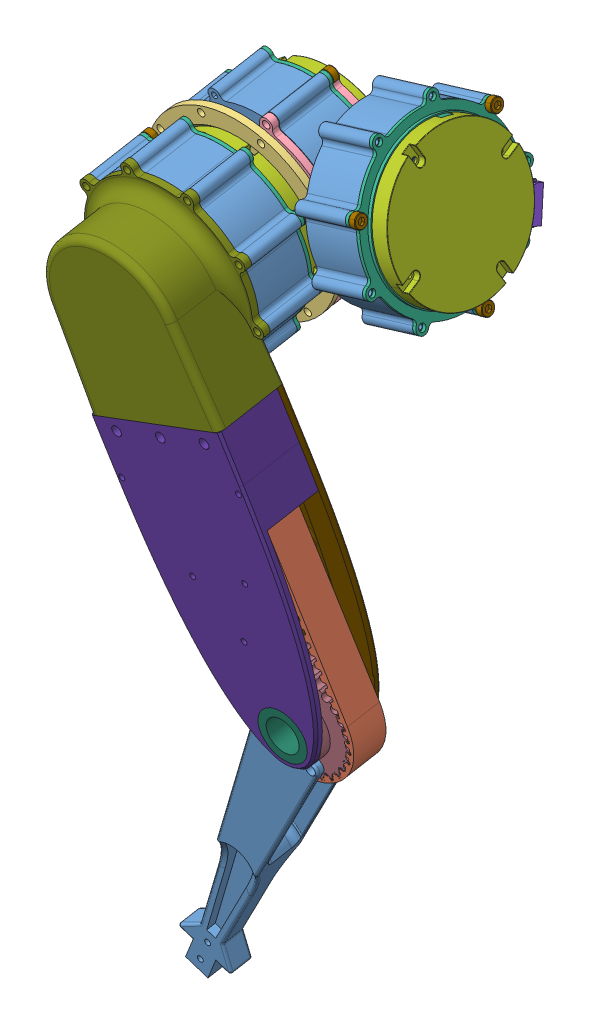
SolidWorks assembly 左机械腿装配体, configuration 默认. Lengths in mm.
Overall size (149.76 378.63 154.43).
74 component instances, 22 part files, 39 mates.
Components (placement in the parent):
- CyberGearmotor.stp-1: CyberGearmotor.stp [默认] at (88.0352 214.6966 202.2626) x (-0.711569 -0.699745 -0.063453) z (-0.039645 0.130153 -0.990701) size (96.28 96.17 36.5)
  - ASM0002_ASM_1_ASM.stp-1: ASM0002_ASM_1_ASM.stp [默认] at origin size (96.28 96.17 36.5)
    - ASM0002_ASM_1_ASM_1_ASM.stp-1: ASM0002_ASM_1_ASM_1_ASM.stp [默认] at origin size (96.28 96.17 36.5)
      - 0714_ASM_1_ASM_1_ASM_1_ASM.stp-1: 0714_ASM_1_ASM_1_ASM_1_ASM.stp [默认] at origin size (96.28 96.17 36.5)
        - 3_1_02_067_0003_ASM_ASM_1_ASM_1_ASM.stp-1: 3_1_02_067_0003_ASM_ASM_1_ASM_1_ASM.stp [默认] at origin size (96.28 96.17 36.5)
          - 3_1_02_067_0003_ASM_1_ASM_1_ASM_ASM.stp-1: 3_1_02_067_0003_ASM_1_ASM_1_ASM_ASM.stp [默认] at origin size (96.28 96.17 36.5)
            - 1_1_06_EB673-504_1_1_1_1_1.stp-1: 1_1_06_EB673-504_1_1_1_1_1.stp [默认] at (39.8324 39.833 -22) size (79.19 78.95 25.5)
            - 1_2_04_670601_1_1_1_1_1.stp-1: 1_2_04_670601_1_1_1_1_1.stp [默认] at (93.9161 79.9966 -44) size (37 37 4)
            - 1_1_02_EB671-500_1_1_1_1_1.stp-1: 1_1_02_EB671-500_1_1_1_1_1.stp [默认] at (93.9161 79.9966 -44.4) x (-0.960973 0.276644 0) z (0 0 1) size (33 33 8.5)
            - 1_2_04_694000_1_1_1_1_1.stp-1: 1_2_04_694000_1_1_1_1_1.stp [默认] at (93.9161 79.9966 -44.5) size (11 11 4)
            - 1_2_06_000213_1_1_1_1_1.stp-1: 1_2_06_000213_1_1_1_1_1.stp [默认] at (93.9161 79.9966 -45.5) size (38.8 36.2 1.5)
            - 1_1_31_QT-642_1_1_1_1_1.stp-1: 1_1_31_QT-642_1_1_1_1_1.stp [默认] at (93.9161 79.9966 -22) x (-0.970555 -0.24088 0) z (0 0 -1) size (79.5 79.36 6)
            - 1_1_06_EB673-502_1_1_1_1_1.stp-1: 1_1_06_EB673-502_1_1_1_1_1.stp [默认] at (93.9161 79.9966 -13) x (-0.515958 -0.856614 0) z (0 0 -1) size (63 63 8)
          - 0518_ASM_2_ASM_1_ASM_1_ASM_1_AS_ASM.stp-1: 0518_ASM_2_ASM_1_ASM_1_ASM_1_AS_ASM.stp [默认] at (93.9161 79.9966 -17.235) x (0.235897 -0.971778 0) z (0 0 1) size (15.5 11.3 5.2)
            - 12345_ASM_1_ASM_2_ASM_1_ASM_1_A_ASM.stp-1: 12345_ASM_1_ASM_2_ASM_1_ASM_1_A_ASM.stp [默认] at origin size (15.5 11.3 5.2)
              - DUANZI_1_3_1_1_1_1_1_1.stp-1: DUANZI_1_3_1_1_1_1_1_1.stp [默认] at (-0.1798 16.5474 0.4329) x (0 0 -1) z (0 1 0) size (5.2 15.5 11.3)
      - LUODING_1_1.stp-1: LUODING_1_1.stp [默认] at (119.9375 52.9941 -20.5) x (-1 0 0) z (0 1 0) size (5.68 3 5.68)
      - LUODING_1_1.stp-2: LUODING_1_1.stp [默认] at (104.2902 116.0331 -20.5) x (-1 0 0) z (0 1 0) size (5.68 3 5.68)
      - LUODING_1_1.stp-3: LUODING_1_1.stp [默认] at (57.5205 70.9626 -20.5) x (-1 0 0) z (0 1 0) size (5.68 3 5.68)
  - 0411-2_4_1_3_1.stp-1: 0411-2_4_1_3_1.stp [默认] at (93.9161 79.9964 -17.5) x (0.235904 -0.971776 0) z (0 0 1) size (58 56.68 1.62)
- 带轮-1: 带轮 [默认] at (-32.2576 196.3768 272.8032) x (-0.787561 0.606131 0.111146) z (-0.039645 0.130153 -0.990701) size (43.22 43.22 15)
- 带轮挡边-1: 带轮挡边 [默认] at (-32.8286 198.3388 257.943) x (-0.787561 0.606131 0.111146) z (-0.039645 0.130153 -0.990701) size (50 50 4)
- 带轮挡边-2: 带轮挡边 [默认] at (-32.0753 195.8659 276.7664) x (-0.136683 -0.982867 -0.123654) z (-0.039645 0.130153 -0.990701) size (50 50 4)
- 膝关节带轮-1: 膝关节带轮 [默认] at (42.7569 42.5696 249.5951) x (0.905586 -0.414358 -0.090675) z (-0.039645 0.130153 -0.990701) size (43.22 43.22 23)
- 轴承-1: 轴承 [默认] at (22.237 54.4332 233.3012) x (-0.618855 -0.781631 -0.077921) z (0.039645 -0.130153 0.990701) size (23 23 4)
- 轴承-2: 轴承 [默认] at (22.9704 52.0254 251.6291) x (0.937799 -0.337392 -0.081853) z (0.039645 -0.130153 0.990701) size (23 23 4)
- 膝关节转轴-1: 膝关节转轴 [默认] at (22.1378 54.7586 230.8244) x (-0.610217 -0.788272 -0.079139) z (0.039645 -0.130153 0.990701) size (21 21 29)
- 大腿根部SLDPRT-3: 大腿根部SLDPRT [默认] at (-27.5965 273.8808 260.5922) x (-0.568547 0.812397 0.12948) z (0.039645 -0.130153 0.990701) size (94.61 80.08 30.19)
- 大腿前部-1: 大腿前部 [默认] at (-12.0598 121.0935 270.1798) x (-0.934453 -0.355964 -0.00937) z (0.353874 -0.925392 -0.135734) size (62 27.01 128.98)
- 大腿前部盖子-1: 大腿前部盖子 [默认] at (1.6543 130.6753 240.6082) x (0.934453 0.355964 0.00937) z (0.353874 -0.925392 -0.135734) size (62 3.5 129)
- 小腿2-1: 小腿2 [默认] at (-5.1862 -5.3475 232.6012) x (-0.422306 -0.90076 -0.101437) z (-0.905586 0.414358 0.090675) size (141.69 21.45 28.63)
- 5m同步带1-1: 5m同步带1 [默认] at (22.3227 53.9177 244.3332) x (0.039645 -0.130153 0.990701) z (0.353874 -0.925392 -0.135734) size (15 46.9 201.91)
- 连接盘-1: 连接盘 [默认] at (-34.2196 204.9655 212.9422) x (-0.449194 0.883325 0.134022) z (0.892554 0.45033 0.023444) size (80.5 13.5 80.5)
- CyberGearmotor.stp-2: CyberGearmotor.stp [默认] at (42.1725 305.1021 174.0853) x (0.012772 -0.991334 -0.130747) z (-0.039645 0.130153 -0.990701) size (96.28 96.17 36.5)
  - ASM0002_ASM_1_ASM.stp-1: ASM0002_ASM_1_ASM.stp [默认] at origin size (96.28 96.17 36.5)
    - ASM0002_ASM_1_ASM_1_ASM.stp-1: ASM0002_ASM_1_ASM_1_ASM.stp [默认] at origin size (96.28 96.17 36.5)
      - 0714_ASM_1_ASM_1_ASM_1_ASM.stp-1: 0714_ASM_1_ASM_1_ASM_1_ASM.stp [默认] at origin size (96.28 96.17 36.5)
        - 3_1_02_067_0003_ASM_ASM_1_ASM_1_ASM.stp-1: 3_1_02_067_0003_ASM_ASM_1_ASM_1_ASM.stp [默认] at origin size (96.28 96.17 36.5)
          - 3_1_02_067_0003_ASM_1_ASM_1_ASM_ASM.stp-1: 3_1_02_067_0003_ASM_1_ASM_1_ASM_ASM.stp [默认] at origin size (96.28 96.17 36.5)
            - 1_1_06_EB673-504_1_1_1_1_1.stp-1: 1_1_06_EB673-504_1_1_1_1_1.stp [默认] at (39.8324 39.833 -22) size (79.19 78.95 25.5)
            - 1_2_04_670601_1_1_1_1_1.stp-1: 1_2_04_670601_1_1_1_1_1.stp [默认] at (93.9161 79.9966 -44) size (37 37 4)
            - 1_1_02_EB671-500_1_1_1_1_1.stp-1: 1_1_02_EB671-500_1_1_1_1_1.stp [默认] at (93.9161 79.9966 -44.4) x (-0.960973 0.276644 0) z (0 0 1) size (33 33 8.5)
            - 1_2_04_694000_1_1_1_1_1.stp-1: 1_2_04_694000_1_1_1_1_1.stp [默认] at (93.9161 79.9966 -44.5) size (11 11 4)
            - 1_2_06_000213_1_1_1_1_1.stp-1: 1_2_06_000213_1_1_1_1_1.stp [默认] at (93.9161 79.9966 -45.5) size (38.8 36.2 1.5)
            - 1_1_31_QT-642_1_1_1_1_1.stp-1: 1_1_31_QT-642_1_1_1_1_1.stp [默认] at (93.9161 79.9966 -22) x (-0.970555 -0.24088 0) z (0 0 -1) size (79.5 79.36 6)
            - 1_1_06_EB673-502_1_1_1_1_1.stp-1: 1_1_06_EB673-502_1_1_1_1_1.stp [默认] at (93.9161 79.9966 -13) x (-0.515958 -0.856614 0) z (0 0 -1) size (63 63 8)
          - 0518_ASM_2_ASM_1_ASM_1_ASM_1_AS_ASM.stp-1: 0518_ASM_2_ASM_1_ASM_1_ASM_1_AS_ASM.stp [默认] at (93.9161 79.9966 -17.235) x (0.235897 -0.971778 0) z (0 0 1) size (15.5 11.3 5.2)
            - 12345_ASM_1_ASM_2_ASM_1_ASM_1_A_ASM.stp-1: 12345_ASM_1_ASM_2_ASM_1_ASM_1_A_ASM.stp [默认] at origin size (15.5 11.3 5.2)
              - DUANZI_1_3_1_1_1_1_1_1.stp-1: DUANZI_1_3_1_1_1_1_1_1.stp [默认] at (-0.1798 16.5474 0.4329) x (0 0 -1) z (0 1 0) size (5.2 15.5 11.3)
      - LUODING_1_1.stp-1: LUODING_1_1.stp [默认] at (119.9375 52.9941 -20.5) x (-1 0 0) z (0 1 0) size (5.68 3 5.68)
      - LUODING_1_1.stp-2: LUODING_1_1.stp [默认] at (104.2902 116.0331 -20.5) x (-1 0 0) z (0 1 0) size (5.68 3 5.68)
      - LUODING_1_1.stp-3: LUODING_1_1.stp [默认] at (57.5205 70.9626 -20.5) x (-1 0 0) z (0 1 0) size (5.68 3 5.68)
  - 0411-2_4_1_3_1.stp-1: 0411-2_4_1_3_1.stp [默认] at (93.9161 79.9964 -17.5) x (0.235904 -0.971776 0) z (0 0 1) size (58 56.68 1.62)
- 肩关节连接器-1: 肩关节连接器 [默认] at (-0.5795 143.262 203.6917) x (0.012746 -0.991334 -0.130746) z (0.999133 0.017811 -0.037643) size (67.92 36.71 40.7)
- CyberGearmotor.stp-3: CyberGearmotor.stp [默认] at (56.3683 218.9179 320.1116) x (0.161386 -0.529819 -0.832614) z (0.956605 0.291387 0) size (96.28 96.17 36.5)
  - ASM0002_ASM_1_ASM.stp-1: ASM0002_ASM_1_ASM.stp [默认] at origin size (96.28 96.17 36.5)
    - ASM0002_ASM_1_ASM_1_ASM.stp-1: ASM0002_ASM_1_ASM_1_ASM.stp [默认] at origin size (96.28 96.17 36.5)
      - 0714_ASM_1_ASM_1_ASM_1_ASM.stp-1: 0714_ASM_1_ASM_1_ASM_1_ASM.stp [默认] at origin size (96.28 96.17 36.5)
        - 3_1_02_067_0003_ASM_ASM_1_ASM_1_ASM.stp-1: 3_1_02_067_0003_ASM_ASM_1_ASM_1_ASM.stp [默认] at origin size (96.28 96.17 36.5)
          - 3_1_02_067_0003_ASM_1_ASM_1_ASM_ASM.stp-1: 3_1_02_067_0003_ASM_1_ASM_1_ASM_ASM.stp [默认] at origin size (96.28 96.17 36.5)
            - 1_1_06_EB673-504_1_1_1_1_1.stp-1: 1_1_06_EB673-504_1_1_1_1_1.stp [默认] at (39.8324 39.833 -22) size (79.19 78.95 25.5)
            - 1_2_04_670601_1_1_1_1_1.stp-1: 1_2_04_670601_1_1_1_1_1.stp [默认] at (93.9161 79.9966 -44) size (37 37 4)
            - 1_1_02_EB671-500_1_1_1_1_1.stp-1: 1_1_02_EB671-500_1_1_1_1_1.stp [默认] at (93.9161 79.9966 -44.4) x (-0.960973 0.276644 0) z (0 0 1) size (33 33 8.5)
            - 1_2_04_694000_1_1_1_1_1.stp-1: 1_2_04_694000_1_1_1_1_1.stp [默认] at (93.9161 79.9966 -44.5) size (11 11 4)
            - 1_2_06_000213_1_1_1_1_1.stp-1: 1_2_06_000213_1_1_1_1_1.stp [默认] at (93.9161 79.9966 -45.5) size (38.8 36.2 1.5)
            - 1_1_31_QT-642_1_1_1_1_1.stp-1: 1_1_31_QT-642_1_1_1_1_1.stp [默认] at (93.9161 79.9966 -22) x (-0.970555 -0.24088 0) z (0 0 -1) size (79.5 79.36 6)
            - 1_1_06_EB673-502_1_1_1_1_1.stp-1: 1_1_06_EB673-502_1_1_1_1_1.stp [默认] at (93.9161 79.9966 -13) x (-0.515958 -0.856614 0) z (0 0 -1) size (63 63 8)
          - 0518_ASM_2_ASM_1_ASM_1_ASM_1_AS_ASM.stp-1: 0518_ASM_2_ASM_1_ASM_1_ASM_1_AS_ASM.stp [默认] at (93.9161 79.9966 -17.235) x (0.235897 -0.971778 0) z (0 0 1) size (15.5 11.3 5.2)
            - 12345_ASM_1_ASM_2_ASM_1_ASM_1_A_ASM.stp-1: 12345_ASM_1_ASM_2_ASM_1_ASM_1_A_ASM.stp [默认] at origin size (15.5 11.3 5.2)
              - DUANZI_1_3_1_1_1_1_1_1.stp-1: DUANZI_1_3_1_1_1_1_1_1.stp [默认] at (-0.1798 16.5474 0.4329) x (0 0 -1) z (0 1 0) size (5.2 15.5 11.3)
      - LUODING_1_1.stp-1: LUODING_1_1.stp [默认] at (119.9375 52.9941 -20.5) x (-1 0 0) z (0 1 0) size (5.68 3 5.68)
      - LUODING_1_1.stp-2: LUODING_1_1.stp [默认] at (104.2902 116.0331 -20.5) x (-1 0 0) z (0 1 0) size (5.68 3 5.68)
      - LUODING_1_1.stp-3: LUODING_1_1.stp [默认] at (57.5205 70.9626 -20.5) x (-1 0 0) z (0 1 0) size (5.68 3 5.68)
  - 0411-2_4_1_3_1.stp-1: 0411-2_4_1_3_1.stp [默认] at (93.9161 79.9964 -17.5) x (0.235904 -0.971776 0) z (0 0 1) size (58 56.68 1.62)
Mates (geometry in assembly coordinates):
- 同心1: concentric aligned: cylinder of CyberGearmotor.stp-1/ASM0002_ASM_1_ASM.stp-1/ASM0002_ASM_1_ASM_1_ASM.stp-1/0714_ASM_1_ASM_1_ASM_1_ASM.stp-1/3_1_02_067_0003_ASM_ASM_1_ASM_1_ASM.stp-1/3_1_02_067_0003_ASM_1_ASM_1_ASM_ASM.stp-1/1_1_02_EB671-500_1_1_1_1_1.stp-1 through (-33.1497 199.393 249.9184) axis (0.039645 -0.130153 0.990701) radius 16.5; cylinder of 带轮挡边-1 through (-32.9872 198.8594 253.9802) axis (0.039645 -0.130153 0.990701) radius 25
- 重合1: coincident anti-aligned: plane of CyberGearmotor.stp-1/ASM0002_ASM_1_ASM.stp-1/ASM0002_ASM_1_ASM_1_ASM.stp-1/0714_ASM_1_ASM_1_ASM_1_ASM.stp-1/3_1_02_067_0003_ASM_ASM_1_ASM_1_ASM.stp-1/3_1_02_067_0003_ASM_1_ASM_1_ASM_ASM.stp-1/1_1_02_EB671-500_1_1_1_1_1.stp-1 through (-32.9872 198.8594 253.9802) normal (0.039645 -0.130153 0.990701); plane of 带轮挡边-1 through (-32.9872 198.8594 253.9802) normal (-0.039645 0.130153 -0.990701)
- 重合4: coincident anti-aligned: plane of 带轮-1 through (-22.006 216.4662 259.8914) normal (-0.039645 0.130153 -0.990701); plane of 带轮挡边-1 through (-32.8286 198.3388 257.943) normal (0.039645 -0.130153 0.990701)
- 同心12: concentric aligned: cylinder of CyberGearmotor.stp-1/ASM0002_ASM_1_ASM.stp-1/ASM0002_ASM_1_ASM_1_ASM.stp-1/0714_ASM_1_ASM_1_ASM_1_ASM.stp-1/3_1_02_067_0003_ASM_ASM_1_ASM_1_ASM.stp-1/3_1_02_067_0003_ASM_1_ASM_1_ASM_ASM.stp-1/1_1_02_EB671-500_1_1_1_1_1.stp-1 through (-33.1497 199.393 249.9184) axis (0.039645 -0.130153 0.990701) radius 16.5; cylinder of 带轮挡边-2 through (-32.2339 196.3865 272.8036) axis (0.039645 -0.130153 0.990701) radius 25
- 重合5: coincident anti-aligned: plane of 带轮-1 through (-21.4113 214.5139 274.7519) normal (0.039645 -0.130153 0.990701); plane of 带轮挡边-2 through (-32.2339 196.3865 272.8036) normal (-0.039645 0.130153 -0.990701)
- 同心20: concentric aligned: cylinder of 轴承-1 through (22.3955 53.9126 237.264) axis (-0.039645 0.130153 -0.990701) radius 8.5; cylinder of 膝关节转轴-1 through (23.2479 51.1143 258.564) axis (-0.039645 0.130153 -0.990701) radius 8.5
- 重合12: coincident anti-aligned: plane of CyberGearmotor.stp-1/ASM0002_ASM_1_ASM.stp-1/ASM0002_ASM_1_ASM_1_ASM.stp-1/0714_ASM_1_ASM_1_ASM_1_ASM.stp-1/3_1_02_067_0003_ASM_ASM_1_ASM_1_ASM.stp-1/3_1_02_067_0003_ASM_1_ASM_1_ASM_ASM.stp-1/1_1_06_EB673-504_1_1_1_1_1.stp-1 through (-32.943 198.4519 250.8968) normal (0.039645 -0.130153 0.990701); plane of 大腿根部SLDPRT-3 through (-27.5965 273.8808 260.5922) normal (-0.039645 0.130153 -0.990701)
- 重合17: coincident anti-aligned: plane of 大腿根部SLDPRT-3 through (15.3775 160.7873 271.2684) normal (0.039645 -0.130153 0.990701); plane of 大腿前部-1 through (-12.1787 121.4839 267.2077) normal (-0.039645 0.130153 -0.990701)
- 重合18: coincident anti-aligned: plane of 大腿根部SLDPRT-3 through (10.7684 173.5553 245.8768) normal (0.353874 -0.925392 -0.135734); plane of 大腿前部-1 through (-25.3324 155.8815 272.253) normal (-0.353874 0.925392 0.135734)
- 重合21: coincident anti-aligned: plane of 大腿根部SLDPRT-3 through (-41.5771 143.0133 243.9591) normal (-0.934453 -0.355964 -0.00937); plane of 大腿前部-1 through (-31.8431 117.4792 243.2432) normal (0.934453 0.355964 0.00937)
- 同心32: concentric anti-aligned: cylinder of 膝关节转轴-1 through (23.2479 51.1143 258.564) axis (-0.039645 0.130153 -0.990701) radius 8.5; cylinder of 大腿前部-1 through (23.1686 51.3746 256.5826) axis (0.039645 -0.130153 0.990701) radius 8.5
- 重合23: coincident aligned: plane of 膝关节转轴-1 through (23.2876 50.9842 259.5547) normal (0.039645 -0.130153 0.990701); plane of 大腿前部-1 through (-12.0598 121.0935 270.1798) normal (0.039645 -0.130153 0.990701)
- 重合32: coincident anti-aligned: plane of 带轮挡边-1 through (-32.8286 198.3388 257.943) normal (0.039645 -0.130153 0.990701); plane of 5m同步带1-1 through (40.3855 61.8878 237.0871) normal (-0.039645 0.130153 -0.990701)
- 同心44: concentric aligned: cylinder of 带轮挡边-1 through (-32.9872 198.8594 253.9802) axis (0.039645 -0.130153 0.990701) radius 25; cylinder of 5m同步带1-1 through (-32.5312 197.3626 265.3733) axis (0.039645 -0.130153 0.990701) radius 23.448
- 同心47: concentric anti-aligned: cylinder of 膝关节带轮-1 through (22.3757 53.9777 236.7686) axis (0.039645 -0.130153 0.990701) radius 10.5; cylinder of 膝关节转轴-1 through (23.2479 51.1143 258.564) axis (-0.039645 0.130153 -0.990701) radius 8.5
- 重合36: coincident anti-aligned: plane of 膝关节带轮-1 through (16.5319 31.9781 249.2531) normal (0.039645 -0.130153 0.990701); plane of 轴承-2 through (22.9704 52.0254 251.6291) normal (-0.039645 0.130153 -0.990701)
- 重合38: coincident anti-aligned: plane of 带轮-1 through (-22.006 216.4662 259.8914) normal (-0.039645 0.130153 -0.990701); plane of 带轮挡边-1 through (-32.8286 198.3388 257.943) normal (0.039645 -0.130153 0.990701)
- 重合39: coincident aligned: plane of 带轮-1 through (-21.4113 214.5139 274.7519) normal (0.039645 -0.130153 0.990701); plane of 膝关节带轮-1 through (16.5319 31.9781 249.2531) normal (0.039645 -0.130153 0.990701)
- 重合41: coincident anti-aligned: plane of 膝关节带轮-1 through (22.3677 53.8617 237.2584) normal (-0.039645 0.130153 -0.990701); plane of 轴承-1 through (22.3955 53.9126 237.264) normal (0.039645 -0.130153 0.990701)
- 重合42: coincident anti-aligned: plane of 膝关节带轮-1 through (16.5319 31.9781 249.2531) normal (0.039645 -0.130153 0.990701); plane of 小腿2-1 through (-4.6907 -6.9744 244.985) normal (-0.039645 0.130153 -0.990701)
- 同心50: concentric aligned: cylinder of 膝关节带轮-1 through (7.3523 48.4747 236.6468) axis (-0.039645 0.130153 -0.990701) radius 1.65; cylinder of 小腿2-1 through (9.2157 42.3575 283.2098) axis (-0.039645 0.130153 -0.990701) radius 2.1
- 同心51: concentric aligned: cylinder of 膝关节带轮-1 through (15.6188 39.5655 235.1456) axis (-0.039645 0.130153 -0.990701) radius 1.65; cylinder of 小腿2-1 through (17.4821 33.4483 281.7086) axis (-0.039645 0.130153 -0.990701) radius 2.1
- 同心53: concentric aligned: circle of 轴承-2; cylinder of 膝关节转轴-1 through (22.3361 54.1078 235.7779) axis (0.039645 -0.130153 0.990701) radius 7
- 重合44: coincident anti-aligned: plane of 大腿根部SLDPRT-3 through (14.4261 163.911 247.4916) normal (-0.039645 0.130153 -0.990701); plane of 大腿前部盖子-1 through (1.7733 130.2848 243.5803) normal (0.039645 -0.130153 0.990701)
- 同心54: concentric anti-aligned: cylinder of 大腿根部SLDPRT-3 through (3.5122 161.5684 271.8458) axis (0.039645 -0.130153 0.990701) radius 1.65; cylinder of 大腿前部盖子-1 through (2.5607 164.692 248.069) axis (-0.039645 0.130153 -0.990701) radius 2.1
- 同心55: concentric anti-aligned: cylinder of 大腿根部SLDPRT-3 through (-35.7349 146.6179 271.4523) axis (0.039645 -0.130153 0.990701) radius 1.65; cylinder of 大腿前部盖子-1 through (-36.6863 149.7415 247.6755) axis (-0.039645 0.130153 -0.990701) radius 2.1
- 重合45: coincident anti-aligned: plane of CyberGearmotor.stp-1/ASM0002_ASM_1_ASM.stp-1/ASM0002_ASM_1_ASM_1_ASM.stp-1/0714_ASM_1_ASM_1_ASM_1_ASM.stp-1/3_1_02_067_0003_ASM_ASM_1_ASM_1_ASM.stp-1/3_1_02_067_0003_ASM_1_ASM_1_ASM_ASM.stp-1/1_1_06_EB673-502_1_1_1_1_1.stp-1 through (-34.4342 203.61 217.8197) normal (-0.039645 0.130153 -0.990701); plane of 连接盘-1 through (-34.0214 204.3147 217.8957) normal (0.039645 -0.130153 0.990701)
- 同心56: concentric aligned: cylinder of CyberGearmotor.stp-1/ASM0002_ASM_1_ASM.stp-1/ASM0002_ASM_1_ASM_1_ASM.stp-1/0714_ASM_1_ASM_1_ASM_1_ASM.stp-1/3_1_02_067_0003_ASM_ASM_1_ASM_1_ASM.stp-1/3_1_02_067_0003_ASM_1_ASM_1_ASM_ASM.stp-1/1_1_06_EB673-502_1_1_1_1_1.stp-1 through (-34.117 202.5687 225.7453) axis (-0.039645 0.130153 -0.990701) radius 31.5; cylinder of 连接盘-1 through (-34.4342 203.61 217.8197) axis (-0.039645 0.130153 -0.990701) radius 40.25
- 同心57: concentric aligned: cylinder of CyberGearmotor.stp-1/ASM0002_ASM_1_ASM.stp-1/ASM0002_ASM_1_ASM_1_ASM.stp-1/0714_ASM_1_ASM_1_ASM_1_ASM.stp-1/3_1_02_067_0003_ASM_ASM_1_ASM_1_ASM.stp-1/3_1_02_067_0003_ASM_1_ASM_1_ASM_ASM.stp-1/1_1_31_QT-642_1_1_1_1_1.stp-1 through (2.8758 196.6562 223.9928) axis (-0.039645 0.130153 -0.990701) radius 1.55; cylinder of 连接盘-1 through (2.5388 197.7625 215.5719) axis (-0.039645 0.130153 -0.990701) radius 1.6
- 同心61: concentric aligned: cylinder of CyberGearmotor.stp-1/ASM0002_ASM_1_ASM.stp-1/ASM0002_ASM_1_ASM_1_ASM.stp-1/0714_ASM_1_ASM_1_ASM_1_ASM.stp-1/3_1_02_067_0003_ASM_ASM_1_ASM_1_ASM.stp-1/3_1_02_067_0003_ASM_1_ASM_1_ASM_ASM.stp-1/1_1_06_EB673-502_1_1_1_1_1.stp-1 through (-34.117 202.5687 225.7453) axis (-0.039645 0.130153 -0.990701) radius 31.5; cylinder of CyberGearmotor.stp-2/ASM0002_ASM_1_ASM.stp-1/ASM0002_ASM_1_ASM_1_ASM.stp-1/0714_ASM_1_ASM_1_ASM_1_ASM.stp-1/3_1_02_067_0003_ASM_ASM_1_ASM_1_ASM.stp-1/3_1_02_067_0003_ASM_1_ASM_1_ASM_ASM.stp-1/1_1_06_EB673-502_1_1_1_1_1.stp-1 through (-35.7623 207.9701 184.6312) axis (-0.039645 0.130153 -0.990701) radius 31.5
- 重合48: coincident anti-aligned: plane of 连接盘-1 through (-34.2196 204.9655 212.9422) normal (-0.039645 0.130153 -0.990701); plane of CyberGearmotor.stp-2/ASM0002_ASM_1_ASM.stp-1/ASM0002_ASM_1_ASM_1_ASM.stp-1/0714_ASM_1_ASM_1_ASM_1_ASM.stp-1/3_1_02_067_0003_ASM_ASM_1_ASM_1_ASM.stp-1/3_1_02_067_0003_ASM_1_ASM_1_ASM_ASM.stp-1/1_1_02_EB671-500_1_1_1_1_1.stp-1 through (-34.6324 204.2607 212.8661) normal (0.039645 -0.130153 0.990701)
- 同心70: concentric anti-aligned: cylinder of CyberGearmotor.stp-2/ASM0002_ASM_1_ASM.stp-1/ASM0002_ASM_1_ASM_1_ASM.stp-1/0714_ASM_1_ASM_1_ASM_1_ASM.stp-1/3_1_02_067_0003_ASM_ASM_1_ASM_1_ASM.stp-1/3_1_02_067_0003_ASM_1_ASM_1_ASM_ASM.stp-1/1_1_31_QT-642_1_1_1_1_1.stp-1 through (-35.7425 207.905 185.1265) axis (-0.039645 0.130153 -0.990701) radius 32; cylinder of 肩关节连接器-1 through (-35.8614 208.2954 182.1544) axis (0.039645 -0.130153 0.990701) radius 32
- 重合51: coincident anti-aligned: plane of CyberGearmotor.stp-2/ASM0002_ASM_1_ASM.stp-1/ASM0002_ASM_1_ASM_1_ASM.stp-1/0714_ASM_1_ASM_1_ASM_1_ASM.stp-1/3_1_02_067_0003_ASM_ASM_1_ASM_1_ASM.stp-1/3_1_02_067_0003_ASM_1_ASM_1_ASM_ASM.stp-1/1_1_31_QT-642_1_1_1_1_1.stp-1 through (-35.7425 207.905 185.1265) normal (-0.039645 0.130153 -0.990701); plane of 肩关节连接器-1 through (-1.6974 146.9323 175.7539) normal (0.039645 -0.130153 0.990701)
- 同心71: concentric aligned: cylinder of CyberGearmotor.stp-2/ASM0002_ASM_1_ASM.stp-1/ASM0002_ASM_1_ASM_1_ASM.stp-1/0714_ASM_1_ASM_1_ASM_1_ASM.stp-1/3_1_02_067_0003_ASM_ASM_1_ASM_1_ASM.stp-1/3_1_02_067_0003_ASM_1_ASM_1_ASM_ASM.stp-1/1_1_06_EB673-504_1_1_1_1_1.stp-1 through (-5.6948 230.1941 187.892) axis (0.039645 -0.130153 0.990701) radius 1.25; cylinder of 肩关节连接器-1 through (-6.7189 233.5559 162.3022) axis (0.039645 -0.130153 0.990701) radius 1.6
- 重合52: coincident anti-aligned: plane of 肩关节连接器-1 through (26.2262 151.4271 203.6917) normal (0.956605 0.291387 0); plane of CyberGearmotor.stp-3/ASM0002_ASM_1_ASM.stp-1/ASM0002_ASM_1_ASM_1_ASM.stp-1/0714_ASM_1_ASM_1_ASM_1_ASM.stp-1/3_1_02_067_0003_ASM_ASM_1_ASM_1_ASM.stp-1/3_1_02_067_0003_ASM_1_ASM_1_ASM_ASM.stp-1/1_1_02_EB671-500_1_1_1_1_1.stp-1 through (5.7214 218.743 197.6094) normal (-0.956605 -0.291387 0)
- 同心72: concentric anti-aligned: cylinder of 肩关节连接器-1 through (-37.8855 205.4601 197.6094) axis (0.956605 0.291387 0) radius 21; cylinder of CyberGearmotor.stp-3/ASM0002_ASM_1_ASM.stp-1/ASM0002_ASM_1_ASM_1_ASM.stp-1/0714_ASM_1_ASM_1_ASM_1_ASM.stp-1/3_1_02_067_0003_ASM_ASM_1_ASM_1_ASM.stp-1/3_1_02_067_0003_ASM_1_ASM_1_ASM_ASM.stp-1/1_1_02_EB671-500_1_1_1_1_1.stp-1 through (9.6435 219.9377 197.6094) axis (-0.956605 -0.291387 0) radius 16.5
- 同心87: concentric aligned: cylinder of CyberGearmotor.stp-1/ASM0002_ASM_1_ASM.stp-1/ASM0002_ASM_1_ASM_1_ASM.stp-1/0714_ASM_1_ASM_1_ASM_1_ASM.stp-1/3_1_02_067_0003_ASM_ASM_1_ASM_1_ASM.stp-1/3_1_02_067_0003_ASM_1_ASM_1_ASM_ASM.stp-1/1_1_06_EB673-504_1_1_1_1_1.stp-1 through (-33.0205 198.9689 253.147) axis (-0.039645 0.130153 -0.990701) radius 21.5; cylinder of 大腿根部SLDPRT-3 through (-31.9167 195.3453 280.7292) axis (-0.039645 0.130153 -0.990701) radius 29
- 同心91: concentric aligned: cylinder of 带轮-1 through (-36.7524 207.3838 274.4291) axis (0.039645 -0.130153 0.990701) radius 2.05; cylinder of 带轮挡边-2 through (-36.9902 208.1647 268.4849) axis (0.039645 -0.130153 0.990701) radius 2.05
- 平行1: parallel aligned: plane of 大腿前部-1 through (-33.695 113.2877 266.9919) normal (-0.934453 -0.355964 -0.00937); plane of 5m同步带1-1 through (-54.7396 189.9921 257.7233) normal (-0.934453 -0.355964 -0.00937)
